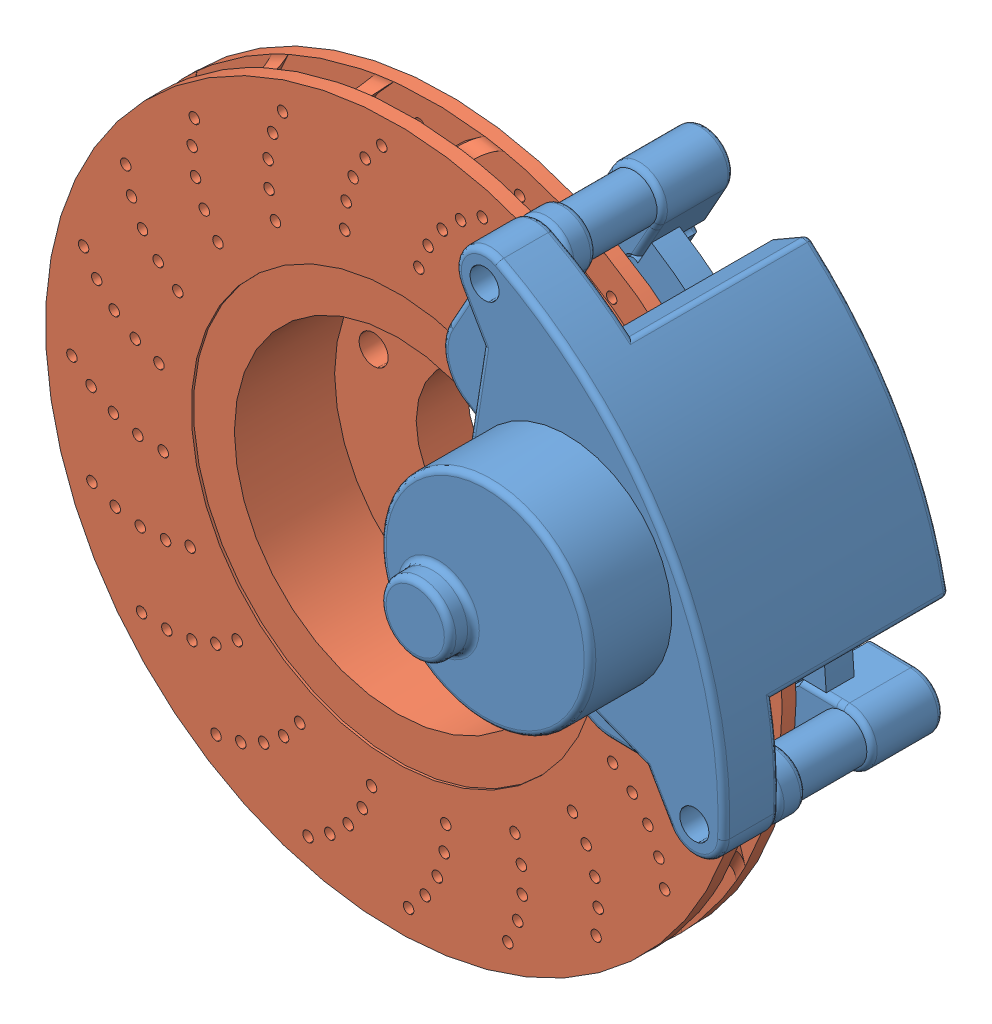
SolidWorks assembly DISC BRAKE ASSEMBLY, configuration Default. Lengths in mm.
Overall size (330 311.08 150).
2 component instances, 2 part files, 2 mates.
Components (placement in the parent):
- Brake-1: Brake [Default] at origin size (144.85 180.88 145)
- Disc-1: Disc [Default] at origin size (300 300 66)
Mates (geometry in assembly coordinates):
- Concentric1: concentric aligned: cylinder of Brake-1 through (0 0 -37) axis (0 0 1) radius 165; cylinder of Disc-1 through (0 0 0) axis (0 0 1) radius 70
- Distance1: distance = 3 mm anti-aligned: plane of Brake-1 through (0 150 -25) normal (0 0 1); plane of Disc-1 through (0 150 -22) normal (0 0 -1)
